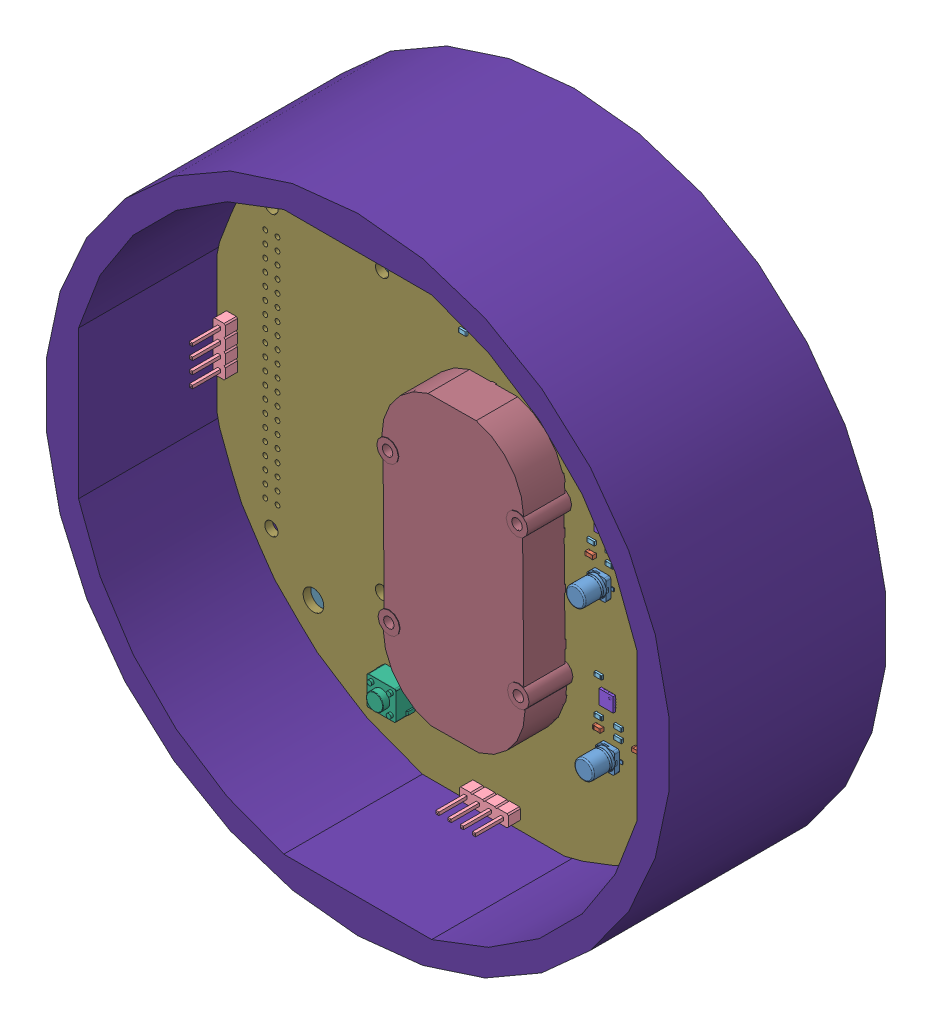
SolidWorks assembly clock, configuration Default. Lengths in mm.
Overall size (130 130 46).
88 component instances, 17 part files, 10 mates.
Components (placement in the parent):
- PCB-1: PCB [Default] at (-45.0911 -5.4506 29.947) size (120 120 26.3)
  - clockclock.step-1: clockclock.step [Default] at origin size (120 120 12.04)
    - C_Elec_4x5.4.step-1: C_Elec_4x5.4.step [Default] at (21.844 -4.826 1.65) size (5.74 5.46 5.4)
      - COMPOUND.step-1: COMPOUND.step [Default] at origin size (5.74 5.46 5.4)
    - C_Elec_4x5.4.step-2: C_Elec_4x5.4.step [Default] at (23.622 -35.052 1.65) size (5.74 5.46 5.4)
      - COMPOUND.step-1: COMPOUND.step [Default] at origin size (5.74 5.46 5.4)
    - C_0603_1608Metric.step-1: C_0603_1608Metric.step [Default] at (29.718 -30.988 1.65) x (-1 0 0) z (0 0 1) size (1.6 0.8 0.8)
      - SOLID.step-1: SOLID.step [Default] at origin size (1.6 0.8 0.8)
    - C_0603_1608Metric.step-2: C_0603_1608Metric.step [Default] at (27.686 -0.508 1.65) x (-1 0 0) z (0 0 1) size (1.6 0.8 0.8)
      - SOLID.step-1: SOLID.step [Default] at origin size (1.6 0.8 0.8)
    - C_0603_1608Metric.step-3: C_0603_1608Metric.step [Default] at (42.164 -8.89 1.65) size (1.6 0.8 0.8)
      - SOLID.step-1: SOLID.step [Default] at origin size (1.6 0.8 0.8)
    - C_0603_1608Metric.step-4: C_0603_1608Metric.step [Default] at (-6.604 36.83 1.65) size (1.6 0.8 0.8)
      - SOLID.step-1: SOLID.step [Default] at origin size (1.6 0.8 0.8)
    - C_0603_1608Metric.step-5: C_0603_1608Metric.step [Default] at (-6.604 28.702 1.65) size (1.6 0.8 0.8)
      - SOLID.step-1: SOLID.step [Default] at origin size (1.6 0.8 0.8)
    - C_0603_1608Metric.step-6: C_0603_1608Metric.step [Default] at (2.032 39.116 1.65) size (1.6 0.8 0.8)
      - SOLID.step-1: SOLID.step [Default] at origin size (1.6 0.8 0.8)
    - C_0603_1608Metric.step-7: C_0603_1608Metric.step [Default] at (6.35 27.94 1.65) size (1.6 0.8 0.8)
      - SOLID.step-1: SOLID.step [Default] at origin size (1.6 0.8 0.8)
    - C_0603_1608Metric.step-8: C_0603_1608Metric.step [Default] at (-2.032 39.116 1.65) size (1.6 0.8 0.8)
      - SOLID.step-1: SOLID.step [Default] at origin size (1.6 0.8 0.8)
    - L_0603_1608Metric.step-1: L_0603_1608Metric.step [Default] at (-2.032 41.91 1.65) size (1.6 0.8 0.8)
      - SOLID-0.step-1: SOLID-0.step [Default] at origin size (1.6 0.8 0.8)
    - PinHeader_1x04_P2.54mm_Vertical.step-1: PinHeader_1x04_P2.54mm_Vertical.step [Default] at (55 3.81 1.65) size (2.54 10.16 11.54)
      - SOLID-1.step-1: SOLID-1.step [Default] at origin size (2.54 10.16 11.54)
    - PinHeader_1x04_P2.54mm_Vertical.step-2: PinHeader_1x04_P2.54mm_Vertical.step [Default] at (-3.81 55 1.65) x (0 1 0) z (0 0 1) size (2.54 10.16 11.54)
      - SOLID-1.step-1: SOLID-1.step [Default] at origin size (2.54 10.16 11.54)
    - PinHeader_1x04_P2.54mm_Vertical.step-3: PinHeader_1x04_P2.54mm_Vertical.step [Default] at (-3.81 -55 1.65) x (0 1 0) z (0 0 1) size (2.54 10.16 11.54)
      - SOLID-1.step-1: SOLID-1.step [Default] at origin size (2.54 10.16 11.54)
    - PinHeader_1x04_P2.54mm_Vertical.step-4: PinHeader_1x04_P2.54mm_Vertical.step [Default] at (-55 3.81 1.65) size (2.54 10.16 11.54)
      - SOLID-1.step-1: SOLID-1.step [Default] at origin size (2.54 10.16 11.54)
    - PinHeader_1x04_P2.54mm_Vertical.step-5: PinHeader_1x04_P2.54mm_Vertical.step [Default] at (-3.81 47.498 1.65) x (0 1 0) z (0 0 1) size (2.54 10.16 11.54)
      - SOLID-1.step-1: SOLID-1.step [Default] at origin size (2.54 10.16 11.54)
    - R_0603_1608Metric.step-1: R_0603_1608Metric.step [Default] at (25.654 -30.988 1.65) x (-1 0 0) z (0 0 1) size (1.6 0.8 0.45)
      - SOLID-2.step-1: SOLID-2.step [Default] at origin size (1.6 0.8 0.45)
    - R_0603_1608Metric.step-2: R_0603_1608Metric.step [Default] at (23.876 -0.508 1.65) x (-1 0 0) z (0 0 1) size (1.6 0.8 0.45)
      - SOLID-2.step-1: SOLID-2.step [Default] at origin size (1.6 0.8 0.45)
    - R_0603_1608Metric.step-3: R_0603_1608Metric.step [Default] at (25.654 -28.956 1.65) size (1.6 0.8 0.45)
      - SOLID-2.step-1: SOLID-2.step [Default] at origin size (1.6 0.8 0.45)
    - R_0603_1608Metric.step-4: R_0603_1608Metric.step [Default] at (23.876 1.778 1.65) size (1.6 0.8 0.45)
      - SOLID-2.step-1: SOLID-2.step [Default] at origin size (1.6 0.8 0.45)
    - R_0603_1608Metric.step-5: R_0603_1608Metric.step [Default] at (21.59 -28.956 1.65) x (-1 0 0) z (0 0 1) size (1.6 0.8 0.45)
      - SOLID-2.step-1: SOLID-2.step [Default] at origin size (1.6 0.8 0.45)
    - R_0603_1608Metric.step-6: R_0603_1608Metric.step [Default] at (20.066 1.778 1.65) x (-1 0 0) z (0 0 1) size (1.6 0.8 0.45)
      - SOLID-2.step-1: SOLID-2.step [Default] at origin size (1.6 0.8 0.45)
    - R_0603_1608Metric.step-7: R_0603_1608Metric.step [Default] at (21.59 -21.59 1.65) x (-1 0 0) z (0 0 1) size (1.6 0.8 0.45)
      - SOLID-2.step-1: SOLID-2.step [Default] at origin size (1.6 0.8 0.45)
    - R_0603_1608Metric.step-8: R_0603_1608Metric.step [Default] at (20.066 9.398 1.65) x (-1 0 0) z (0 0 1) size (1.6 0.8 0.45)
      - SOLID-2.step-1: SOLID-2.step [Default] at origin size (1.6 0.8 0.45)
    - R_0603_1608Metric.step-9: R_0603_1608Metric.step [Default] at (-9.398 32.766 1.65) x (0 -1 0) z (0 0 1) size (1.6 0.8 0.45)
      - SOLID-2.step-1: SOLID-2.step [Default] at origin size (1.6 0.8 0.45)
    - SW_PUSH_6mm_H5mm.step-1: SW_PUSH_6mm_H5mm.step [Default] at (-23.3934 -42.6974 1.65) size (7.17 6 8.5)
      - SOLID-3.step-1: SOLID-3.step [Default] at origin size (7.17 6 8.5)
    - SW_PUSH_6mm_H5mm.step-2: SW_PUSH_6mm_H5mm.step [Default] at (-15.5194 44.8818 1.65) x (-1 0 0) z (0 0 1) size (7.17 6 8.5)
      - SOLID-3.step-1: SOLID-3.step [Default] at origin size (7.17 6 8.5)
    - SW_PUSH_6mm_H5mm.step-3: SW_PUSH_6mm_H5mm.step [Default] at (15.6972 49.2506 1.65) size (7.17 6 8.5)
      - SOLID-3.step-1: SOLID-3.step [Default] at origin size (7.17 6 8.5)
    - SOIC-8_3.9x4.9mm_P1.27mm.step-1: SOIC-8_3.9x4.9mm_P1.27mm.step [Default] at (48.26 -12.446 1.65) x (0 1 0) z (0 0 1) size (6 4.9 1.75)
      - SOLID-4.step-1: SOLID-4.step [Default] at origin size (6 4.9 1.75)
    - UQFN-16-1EP_3x3mm_P0.5mm_EP1.75x1.75mm.step-1: UQFN-16-1EP_3x3mm_P0.5mm_EP1.75x1.75mm.step [Default] at (23.368 -25.146 1.65) x (0 -1 0) z (0 0 1) size (3 3 0.52)
      - SOLID-5.step-1: SOLID-5.step [Default] at origin size (3 3 0.52)
    - UQFN-16-1EP_3x3mm_P0.5mm_EP1.75x1.75mm.step-2: UQFN-16-1EP_3x3mm_P0.5mm_EP1.75x1.75mm.step [Default] at (22.352 5.588 1.65) x (0 -1 0) z (0 0 1) size (3 3 0.52)
      - SOLID-5.step-1: SOLID-5.step [Default] at origin size (3 3 0.52)
    - QFN-32-1EP_5x5mm_P0.5mm_EP3.45x3.45mm.step-1: QFN-32-1EP_5x5mm_P0.5mm_EP3.45x3.45mm.step [Default] at (0 31.75 1.65) size (5 5 0.77)
      - SOLID-6.step-1: SOLID-6.step [Default] at origin size (5 5 0.77)
    - C_0603_1608Metric.step-9: C_0603_1608Metric.step [Default] at (20.066 -0.508 1.65) size (1.6 0.8 0.8)
      - SOLID.step-1: SOLID.step [Default] at origin size (1.6 0.8 0.8)
    - C_0603_1608Metric.step-10: C_0603_1608Metric.step [Default] at (21.59 -30.988 1.65) size (1.6 0.8 0.8)
      - SOLID.step-1: SOLID.step [Default] at origin size (1.6 0.8 0.8)
    - R_0603_1608Metric.step-10: R_0603_1608Metric.step [Default] at (42.164 -15.494 1.65) x (-1 0 0) z (0 0 1) size (1.6 0.8 0.45)
      - SOLID-2.step-1: SOLID-2.step [Default] at origin size (1.6 0.8 0.45)
    - R_0603_1608Metric.step-11: R_0603_1608Metric.step [Default] at (42.164 -12.192 1.65) x (-1 0 0) z (0 0 1) size (1.6 0.8 0.45)
      - SOLID-2.step-1: SOLID-2.step [Default] at origin size (1.6 0.8 0.45)
    - R_0603_1608Metric.step-12: R_0603_1608Metric.step [Default] at (6.096 39.116 1.65) x (-1 0 0) z (0 0 1) size (1.6 0.8 0.45)
      - SOLID-2.step-1: SOLID-2.step [Default] at origin size (1.6 0.8 0.45)
    - R_0603_1608Metric.step-13: R_0603_1608Metric.step [Default] at (-6.604 26.162 1.65) x (-1 0 0) z (0 0 1) size (1.6 0.8 0.45)
      - SOLID-2.step-1: SOLID-2.step [Default] at origin size (1.6 0.8 0.45)
    - SW_DIP_SPSTx04_Slide_6.7x11.72mm_W7.62mm_P2.54mm_LowProfile.step-1: SW_DIP_SPSTx04_Slide_6.7x11.72mm_W7.62mm_P2.54mm_LowProfile.step [Default] at (17.78 28.448 1.65) x (0 -1 0) z (0 0 1) size (11.72 7.82 6)
      - SOLID-7.step-1: SOLID-7.step [Default] at origin size (11.72 7.82 6)
    - BatteryHolder_Keystone_1058_1x2032.step-1: BatteryHolder_Keystone_1058_1x2032.step [Default] at (39.878 13.462 1.65) x (0 1 0) z (0 0 1) size (31.86 16 5.08)
      - SOLID-8.step-1: SOLID-8.step [Default] at origin size (31.86 16 5.08)
    - COMPOUND-9.step-1: COMPOUND-9.step [Default] at origin size (120 120 1.6)
  - BKA30D-1: BKA30D [Default] at (0.0841 -9.5996 10.6) x (-0.008761 0.999962 0) z (-0.999962 -0.008761 0) size (59.5 26.3 31.4)
- face-1: face [Default] at (-45.0911 -5.4506 25.347) size (120 120 2)
- grootewijzer-1: grootewijzer [Default] at (-45.0911 -5.4506 20.347) x (1 0 0) z (0 -1 0) size (58 4 8)
- kleinewijzer-1: kleinewijzer [Default] at (-45.0911 -5.4506 14.347) x (0.229997 0.973191 0) z (0.973191 -0.229997 0) size (48 4 8)
- housing-1: housing [Default] at (-45.0911 -5.4506 25.347) x (1 0 0) z (0 1 0) size (130 45 130)
Mates (geometry in assembly coordinates):
- Concentric1: concentric anti-aligned: cylinder of PCB-1/BKA30D-1 through (-45.0911 -5.4506 25.347) axis (0 0 1) radius 2.85; cylinder of face-1 through (-45.0911 -5.4506 27.347) axis (0 0 -1) radius 2.75
- Coincident1: coincident aligned: plane of PCB-1/BKA30D-1 through (-45.0911 -5.4506 25.347) normal (0 0 -1); plane of face-1 through (-45.0911 -5.4506 25.347) normal (0 0 -1)
- Concentric2: concentric anti-aligned: cylinder of PCB-1/BKA30D-1 through (-45.0911 -5.4506 20.547) axis (0 0 1) radius 2; cylinder of grootewijzer-1 through (-45.0911 -5.4506 22.347) axis (0 0 -1) radius 2
- Distance1: distance = 1 mm anti-aligned: plane of grootewijzer-1 through (-45.0911 -5.4506 24.347) normal (0 0 1); plane of face-1 through (-45.0911 -5.4506 25.347) normal (0 0 -1)
- Concentric3: concentric anti-aligned: cylinder of PCB-1/BKA30D-1 through (-45.0911 -5.4506 14.347) axis (0 0 1) radius 0.75; cylinder of kleinewijzer-1 through (-45.0911 -5.4506 16.347) axis (0 0 -1) radius 0.74
- Coincident3: coincident aligned: plane of PCB-1/BKA30D-1 through (-45.0911 -5.4506 14.347) normal (0 0 -1); plane of kleinewijzer-1 through (-45.0911 -5.4506 14.347) normal (0 0 -1)
- Coincident4: coincident anti-aligned: plane of face-1 through (-45.0911 -5.4506 25.347) normal (0 0 -1); plane of housing-1 through (-45.0911 -5.4506 25.347) normal (0 0 1)
- Concentric4: concentric aligned: cylinder of face-1 through (-45.0911 -5.4506 27.347) axis (0 0 -1) radius 60; cylinder of housing-1 through (-45.0911 -5.4506 60.347) axis (0 0 -1) radius 60
- Coincident5: coincident anti-aligned: circle of PCB-1/clockclock.step-1/COMPOUND-9.step-1; cylinder of housing-1 through (-45.0911 -5.4506 60.347) axis (0 0 -1) radius 60
- Parallel1: parallel aligned: plane of PCB-1/clockclock.step-1/PinHeader_1x04_P2.54mm_Vertical.step-3/SOLID-1.step-1 through (-40.2651 -59.1806 31.597) normal (0 1 0); plane of housing-1 through (-60.4534 -63.4506 -5.4426) normal (0 1 0)
